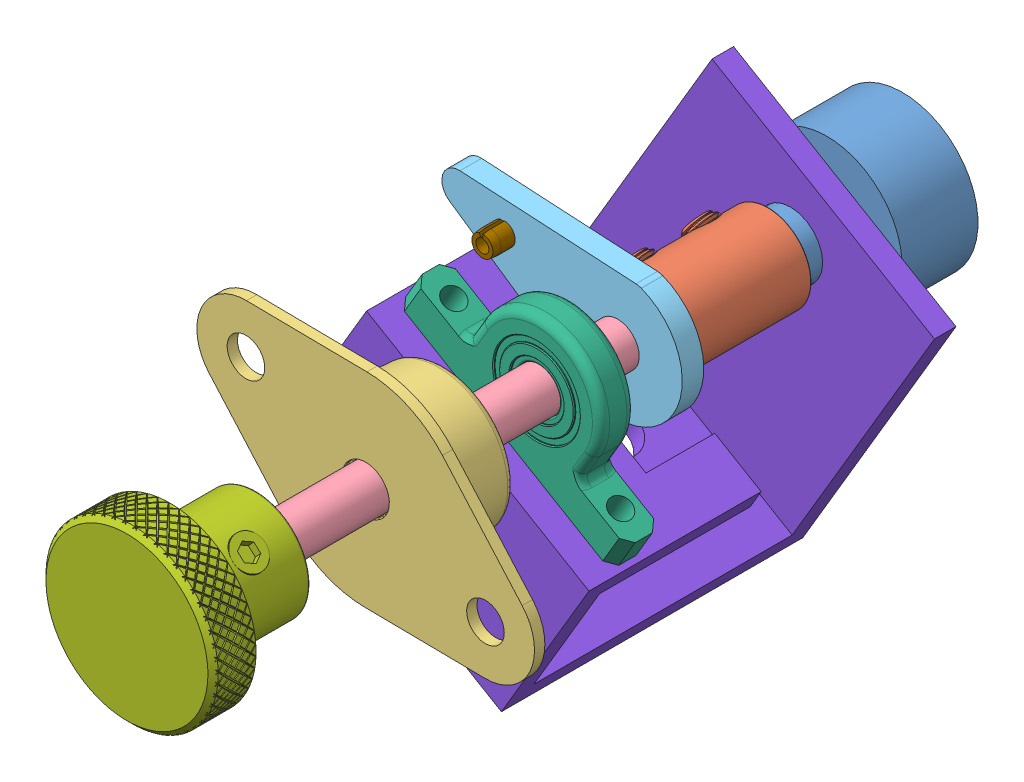
SolidWorks assembly KnobAssm, configuration Default. Lengths in mm.
Overall size (64.7 64.61 114.43).
9 component instances, 9 part files, 16 mates.
Components (placement in the parent):
- Pot-2: Pot [Default] at (-3.5085 -0.0702 31.877) size (22.23 22.23 31.88)
- 6412K110-1: 6412K110 [6412K11] at (-3.5085 -0.0702 61.214) x (0.568304 0.822819 0) z (0 0 1) size (12.7 13.7 19.05)
- 1434K430-1: 1434K430 [1434K43] at (-3.5085 -0.0702 111.0856) x (-0.909157 0.416453 0) z (0 0 -1) size (53.34 30.23 12.19)
- 1327K650-2: 1327K650 [1327K65] at (-3.5085 -0.0702 101.854) x (0.22205 0.975035 0) z (0 0 1) size (6.35 6.35 76.2)
- End Stop-2: End Stop [Default] at (-3.5085 -0.0702 70.739) x (0.322753 0.946483 0) z (0 0 1) size (19.04 36.78 3.17)
- 8600N300-1: 8600N300 [8600N3] at (-3.5085 -0.0702 83.3579) x (0.861084 -0.508463 0) z (0 0 1) size (36.51 19.05 5.08)
- 2577K210-1: 2577K210 [2577K21] at (-3.5085 -0.0702 127.254) x (0.670831 0.74161 0) z (0 0 1) size (25.4 25.4 19.05)
- BasePlate-1: BasePlate [Default] at (-3.2485 -37.0958 86.5329) x (-0.861084 0.508463 0) z (0 0 -1) size (38.1 44.45 44.45)
- 92373A173-1: 92373A173 [92373A173] at (-20.2937 5.6536 73.914) x (0.113427 -0.993546 0) z (0 0 1) size (3.3 3.33 6.35)
Mates (geometry in assembly coordinates):
- Concentric1: concentric aligned: cylinder of Pot-2 through (-3.5085 -0.0702 63.754) axis (0 0 -1) radius 3.175; cylinder of 6412K110-1 through (-3.5085 -0.0702 70.739) axis (0 0 -1) radius 3.175
- Coincident1: coincident anti-aligned: plane of Pot-2 through (-3.5085 -0.0702 51.689) normal (0 0 1); plane of 6412K110-1 through (-3.5085 -0.0702 51.689) normal (0 0 -1)
- Concentric31: concentric aligned: cylinder of 6412K110-1 through (-3.5085 -0.0702 70.739) axis (0 0 -1) radius 3.175; cylinder of 1327K650-2 through (-3.5085 -0.0702 139.954) axis (0 0 -1) radius 3.175
- Coincident2: coincident anti-aligned: plane of Pot-2 through (-3.5085 -0.0702 63.754) normal (0 0 1); circle of 1327K650-2
- Concentric5: concentric aligned: cylinder of 6412K110-1 through (-3.5085 -0.0702 70.739) axis (0 0 -1) radius 6.35; cylinder of 1327K650-2 through (-3.5085 -0.0702 139.954) axis (0 0 -1) radius 3.175
- Concentric6: concentric aligned: cylinder of 1327K650-2 through (-3.5085 -0.0702 139.954) axis (0 0 -1) radius 3.175; cylinder of End Stop-2 through (-3.5085 -0.0702 73.914) axis (0 0 -1) radius 3.175
- Coincident3: coincident anti-aligned: plane of 6412K110-1 through (-3.5085 -0.0702 70.739) normal (0 0 1); plane of End Stop-2 through (-5.4574 -6.7778 70.739) normal (0 0 -1)
- Concentric7: concentric aligned: circle of 1434K430-1; cylinder of 1327K650-2 through (-3.5085 -0.0702 139.954) axis (0 0 -1) radius 3.175
- Concentric8: concentric aligned: cylinder of 1327K650-2 through (-3.5085 -0.0702 139.954) axis (0 0 -1) radius 3.175; cylinder of 8600N300-1 through (-3.5085 -0.0702 83.3579) axis (0 0 -1) radius 3.175
- Coincident4: coincident anti-aligned: plane of 1327K650-2 through (-3.5085 -0.0702 139.954) normal (0 0 1); plane of 2577K210-1 through (-3.5085 -0.0702 139.954) normal (0 0 -1)
- Concentric9: concentric aligned: cylinder of 1327K650-2 through (-3.5085 -0.0702 139.954) axis (0 0 -1) radius 3.175; cylinder of 2577K210-1 through (-3.5085 -0.0702 127.254) axis (0 0 -1) radius 3.175
- Coincident5: coincident anti-aligned: plane of 8600N300-1 through (7.3686 -17.5546 85.8979) normal (-0.508463 -0.861084 0); plane of BasePlate-1 through (-24.7552 1.4142 89.7079) normal (0.508463 0.861084 0)
- Concentric10: concentric aligned: cylinder of 8600N300-1 through (-20.6543 -1.0073 83.3579) axis (0.508463 0.861084 0) radius 1.5875; cylinder of BasePlate-1 through (-24.5517 -7.6076 83.3579) axis (0.508463 0.861084 0) radius 1.5875
- Concentric11: concentric aligned: cylinder of 8600N300-1 through (3.9512 -15.5367 83.3579) axis (0.508463 0.861084 0) radius 1.5875; cylinder of BasePlate-1 through (0.0537 -22.137 83.3579) axis (0.508463 0.861084 0) radius 1.5875
- Concentric13: concentric anti-aligned: cylinder of End Stop-2 through (-20.2937 5.6536 73.914) axis (0 0 1) radius 1.5875; cylinder of 92373A173-1 through (-20.2937 5.6536 77.089) axis (0 0 -1) radius 1.6637
- Coincident7: coincident aligned: plane of End Stop-2 through (-5.4574 -6.7778 70.739) normal (0 0 -1); plane of 92373A173-1 through (-20.2937 5.6536 70.739) normal (0 0 -1)
